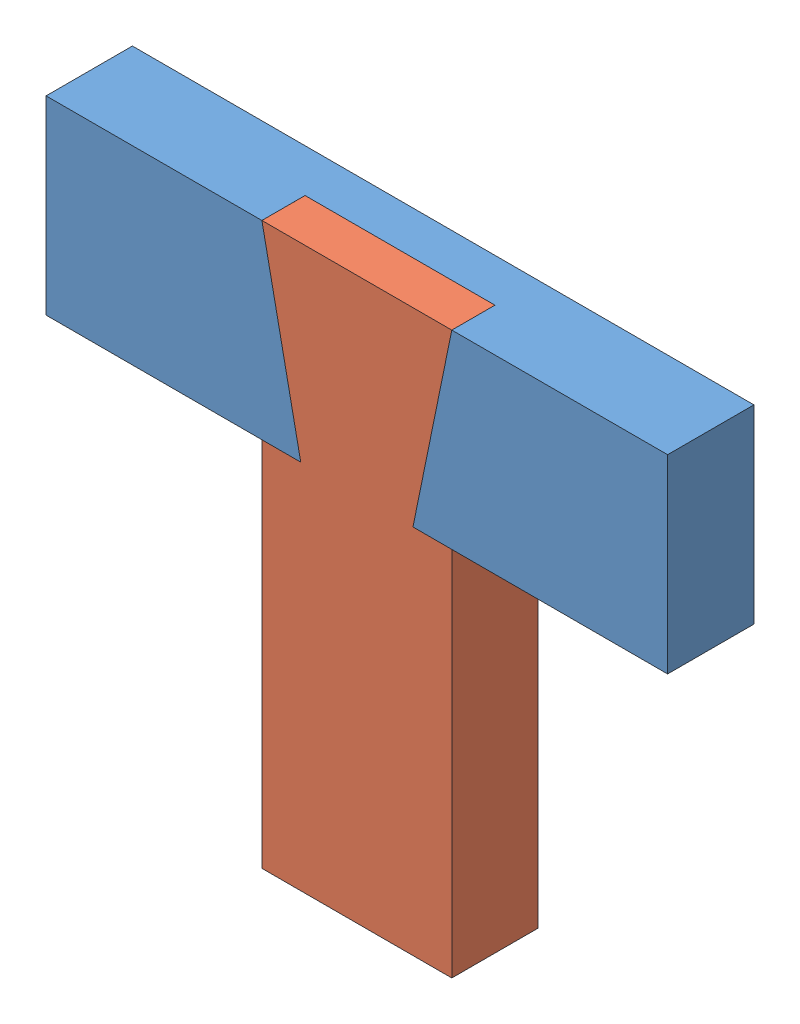
SolidWorks assembly ASSEMBLED, configuration Default. Lengths in mm.
Overall size (144 130 20).
2 component instances, 2 part files, 3 mates.
Components (placement in the parent):
- DOVETAIL SOCKET-1: DOVETAIL SOCKET [Default] at (-112.4091 -18.3439 -10) size (144 44 20)
- DOVETAIL PIN-1: DOVETAIL PIN [Default] at (-18.4091 -104.3439 10) x (-1 0 0) z (0 0 -1) size (44 130 20)
Mates (geometry in assembly coordinates):
- Coincident2: coincident: point of ?; point of ?
- Coincident5: coincident anti-aligned: plane of DOVETAIL SOCKET-1 through (-62.4091 25.6561 0) normal (0 0 1); plane of DOVETAIL PIN-1 through (-18.4091 -104.3439 0) normal (0 0 -1)
- Coincident7: coincident aligned: plane of DOVETAIL SOCKET-1 through (-112.4091 25.6561 10) normal (0 1 0); plane of DOVETAIL PIN-1 through (-18.4091 25.6561 0) normal (0 1 0)
